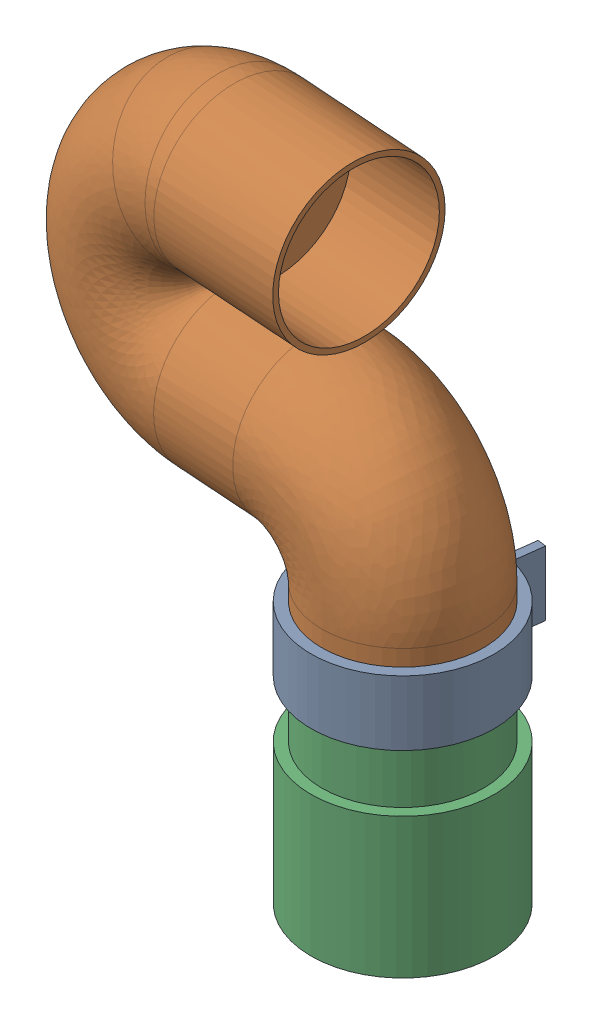
SolidWorks assembly arm_1_assembly, configuration Default. Lengths in mm.
Overall size (442.03 576.37 242.42).
8 component instances, 8 part files, 14 mates.
Components (placement in the parent):
- rotary_joint-1: rotary_joint [Default] at (0 182.84 0) x (-0.123512 0 0.992343) z (-0.992343 0 -0.123512) size (197.58 60 170)
- arm1-1: arm1 [Default] at (0 222.84 0) x (-0.997621 0 -0.06894) z (0.06894 0 -0.997621) size (392.31 353.53 152.88)
- fixed_base-1: fixed_base [Default] x (-0.700898 0 0.713262) z (-0.713262 0 -0.700898) size (170 202.35 170)
- arm 1 motor-1: arm 1 motor [Default] at (-74.9451 139.55 6.4604) x (-0.793757 0 0.608235) z (0 1 0) size (52 52 172)
- arm 1 shaft coupler-1: arm 1 shaft coupler [6853N141] at (0 174.0109 0) x (-0.988241 0 -0.152904) z (0 -1 0) size (38.97 38.89 48.13)
- arm 1 shaft-1: arm 1 shaft [Default] at (0 178 0) x (0.999999 0 0.001014) z (-0.001014 0 0.999999) size (20 86.19 20)
- bushing hub-1: bushing hub [9859T718] at (0 248.315 0) x (0 -1 0) z (0.937636 0 0.347618) size (35.75 63.5 63.5)
- arm ball bearing-1: arm ball bearing [5972K119] at (0 212.84 0) x (0.970752 0 0.240083) z (0 1 0) size (52 52 15)
Mates (geometry in assembly coordinates):
- Coincident4: coincident anti-aligned: plane of arm 1 motor-1 through (0 150 0) normal (0 1 0); plane of arm 1 shaft coupler-1 through (2.8248 150 -18.2573) normal (0 -1 0)
- Concentric2: concentric anti-aligned: cylinder of arm 1 motor-1 through (0 178 0) axis (0 -1 0) radius 6; cylinder of arm 1 shaft coupler-1 through (0 198.0219 0) axis (0 1 0) radius 6
- Concentric3: concentric aligned: circle of fixed_base-1; circle of arm 1 motor-1
- Concentric5: concentric aligned: circle of arm 1 shaft coupler-1; circle of arm 1 shaft-1
- Coincident10: coincident anti-aligned: plane of arm 1 motor-1 through (0 178 0) normal (0 1 0); plane of arm 1 shaft-1 through (0 178 0) normal (0 -1 0)
- Concentric6: concentric anti-aligned: circle of arm 1 shaft-1; circle of bushing hub-1
- Coincident12: coincident aligned: plane of arm 1 shaft-1 through (0 264.19 0) normal (0 1 0); plane of bushing hub-1 through (0 264.19 0) normal (0 1 0)
- Coincident15: coincident anti-aligned: plane of arm1-1 through (0 222.84 0) normal (0 -1 0); plane of rotary_joint-1 through (0 222.84 0) normal (0 1 0)
- Coincident17: coincident anti-aligned: circle of arm1-1; plane of bushing hub-1 through (-11.0369 257.84 29.77) normal (0 -1 0)
- Concentric7: concentric aligned: circle of arm1-1; circle of bushing hub-1
- Concentric8: concentric aligned: circle of rotary_joint-1; circle of arm ball bearing-1
- Distance1: distance = 22.5 mm aligned: plane of arm ball bearing-1 through (6.0621 220.34 -24.5115) normal (0 1 0); plane of rotary_joint-1 through (0 242.84 0) normal (0 1 0)
- Hinge1: hinge anti-aligned: cylinder of arm1-1 through (0 222.84 0) axis (0 1 0) radius 75; cylinder of arm1-1 through (0 242.84 0) axis (0 -1 0) radius 85; plane of rotary_joint-1 through (0 222.84 0) normal (0 -1 0); plane of rotary_joint-1 through (0 222.84 0) normal (0 1 0)
- Coincident20: coincident anti-aligned: plane of fixed_base-1 through (0 6 0) normal (0 1 0); plane of arm 1 motor-1 through (0 6 0) normal (0 -1 0)
